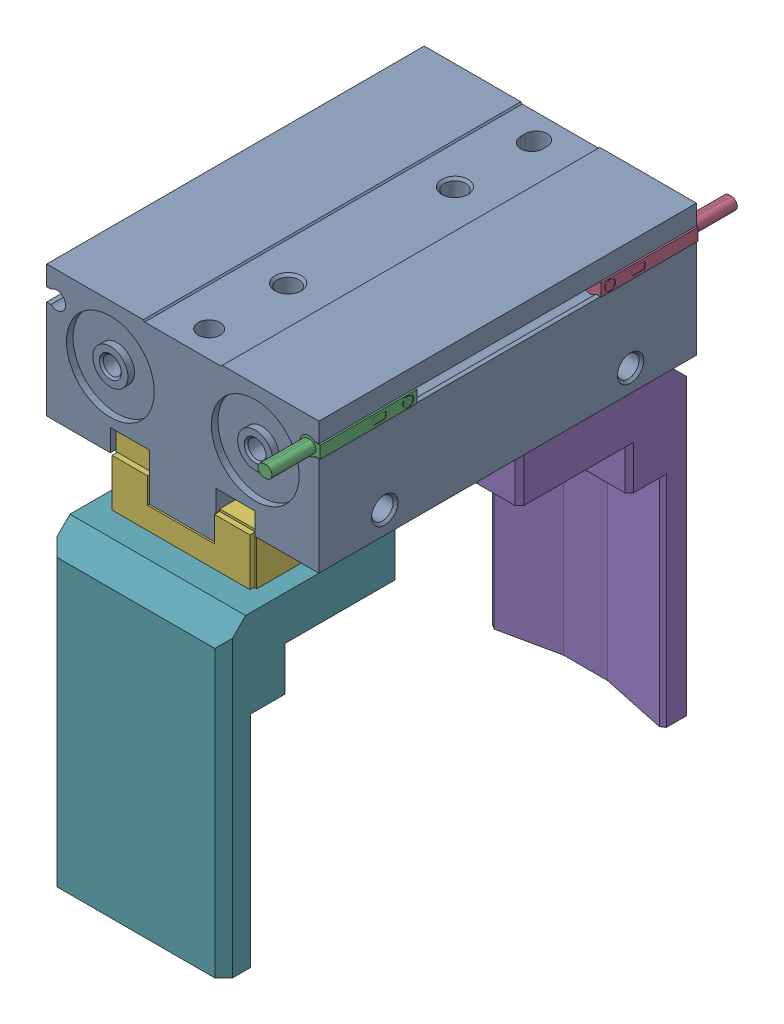
SolidWorks assembly 1-MHF2-20D-M9N(8_0), configuration 默认. Lengths in mm.
Overall size (62.3 111 107.4).
7 component instances, 5 part files, 13 mates.
Components (placement in the parent):
- 1-MHF2-20D_Body(0)-1: 1-MHF2-20D_Body(0) [默认] at origin size (62 35.7 86)
- 1-MHF2-20D_Finger(0)-1: 1-MHF2-20D_Finger(0) [默认] at (0 -41 -10) x (-1 0 0) z (0 0 -1) size (32 17.6 53.4)
- 1-MHF2_D-M9N-1: 1-MHF2_D-M9N [默认] at (28.7 -6 21) x (1 0 0) z (0 0 -1) size (4.6 4 32)
- 1-MHF2_D-M9N-2: 1-MHF2_D-M9N [默认] at (28.7 -6 -21) size (4.6 4 32)
- 1-JHM-上料机械手-003-1: 1-JHM-上料机械手-003 [默认] at (0 -111 -46.2) size (40 70 40)
- 1-镜向MHF2-20D_Finger(0)-3: 1-镜向MHF2-20D_Finger(0) [默认] at (0 -41 10) x (-1 0 0) z (0 0 -1) size (32 17.6 53.4)
- 1-JHM-上料机械手-003-3: 1-JHM-上料机械手-003 [默认] at (0 -111 46.2) x (-1 0 0) z (0 0 -1) size (40 70 40)
Mates (geometry in assembly coordinates):
- LimitDistance1: limit distance = 10 mm aligned: plane of assembly through (0 0 0) normal (0 0 1); plane of 1-MHF2-20D_Finger(0)-1 through (0 -41 -10) normal (0 0 1)
- 重合2: coincident anti-aligned: plane of 1-MHF2-20D_Body(0)-1 through (-7.6 -35.7 43) normal (0 -1 0); plane of 1-MHF2-20D_Finger(0)-1 through (-7.6 -35.7 -43.4) normal (0 1 0)
- 宽度1: width anti-aligned: plane of 1-MHF2-20D_Finger(0)-1 through (16 -29.4 -43.4) normal (1 0 0); plane of 1-MHF2-20D_Finger(0)-1 through (-16 -41 -43.4) normal (-1 0 0); plane of 1-MHF2-20D_Body(0)-1 through (-7.6 -25 43) normal (-1 0 0); plane of 1-MHF2-20D_Body(0)-1 through (7.6 -35.7 43) normal (1 0 0)
- 重合3: coincident anti-aligned: plane of 1-MHF2-20D_Finger(0)-1 through (16 -41 -43.4) normal (0 -1 0); plane of 1-JHM-上料机械手-003-1 through (0 -41 -46.2) normal (0 1 0)
- 同心1: concentric anti-aligned: cylinder of 1-MHF2-20D_Finger(0)-1 through (12 -41 -34.7) axis (0 1 0) radius 1.621; cylinder of 1-JHM-上料机械手-003-1 through (12 -51 -34.7) axis (0 -1 0) radius 4
- 同心2: concentric anti-aligned: cylinder of 1-MHF2-20D_Finger(0)-1 through (12 -41 -18.7) axis (0 1 0) radius 1.621; cylinder of 1-JHM-上料机械手-003-1 through (12 -51 -18.7) axis (0 -1 0) radius 2.25
- 重合4: coincident anti-aligned: plane of 1-镜向MHF2-20D_Finger(0)-3 through (16 -41 43.4) normal (0 -1 0); plane of 1-JHM-上料机械手-003-3 through (0 -41 46.2) normal (0 1 0)
- 同心3: concentric anti-aligned: cylinder of 1-镜向MHF2-20D_Finger(0)-3 through (12 -41 18.7) axis (0 1 0) radius 1.621; cylinder of 1-JHM-上料机械手-003-3 through (12 -51 18.7) axis (0 -1 0) radius 4
- 同心4: concentric anti-aligned: cylinder of 1-镜向MHF2-20D_Finger(0)-3 through (12 -41 34.7) axis (0 1 0) radius 1.621; cylinder of 1-JHM-上料机械手-003-3 through (12 -51 34.7) axis (0 -1 0) radius 4
- 同心5: concentric anti-aligned: cylinder of 1-MHF2-20D_Body(0)-1 through (28.7 -6 43) axis (0 0 -1) radius 2; cylinder of 1-MHF2_D-M9N-2 through (28.7 -6 -43) axis (0 0 1) radius 2
- 重合5: coincident aligned: plane of 1-MHF2-20D_Body(0)-1 through (28.7 -6 -43) normal (0 0 -1); plane of 1-MHF2_D-M9N-2 through (28.7 -6 -43) normal (0 0 -1)
- 同心6: concentric aligned: cylinder of 1-MHF2-20D_Body(0)-1 through (28.7 -6 43) axis (0 0 -1) radius 2; cylinder of 1-MHF2_D-M9N-1 through (28.7 -6 43) axis (0 0 -1) radius 2
- 重合6: coincident aligned: plane of 1-MHF2-20D_Body(0)-1 through (28.7 -6 43) normal (0 0 1); plane of 1-MHF2_D-M9N-1 through (28.7 -6 43) normal (0 0 1)
